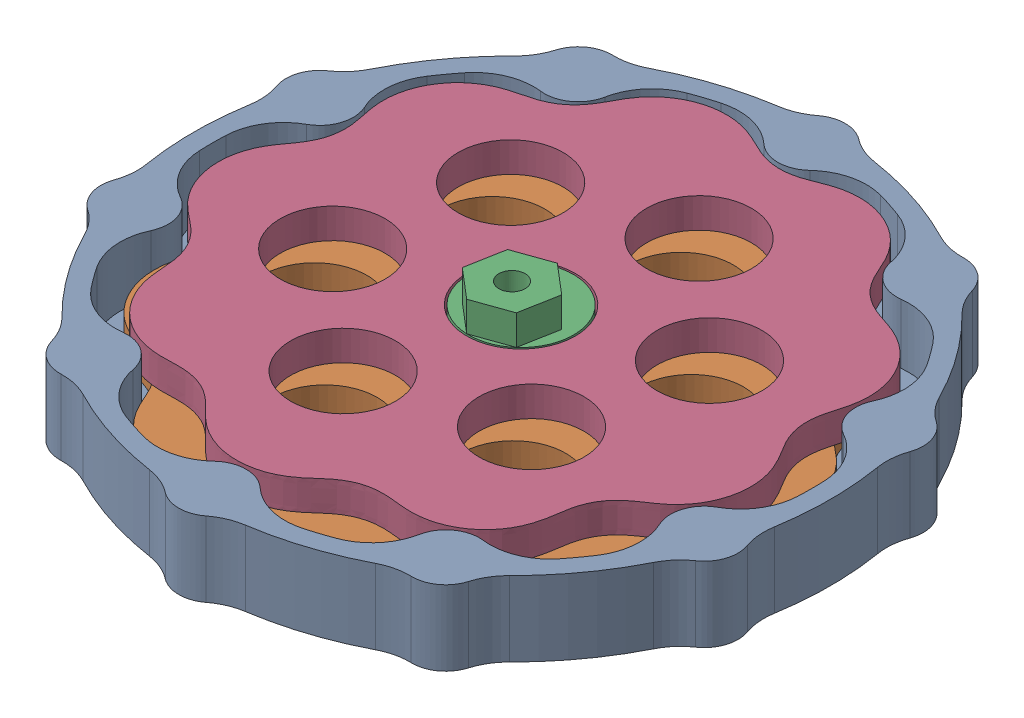
SolidWorks assembly TestPartAssem, configuration Default. Lengths in mm.
Overall size (86.43 14 90.22).
4 component instances, 3 part files, 10 mates.
Components (placement in the parent):
- cycloid_stator-1: cycloid_stator [Default] at (-40.2168 46.6857 65.8886) size (85.08 10 90)
- cycloidal_disk-1: cycloidal_disk [Default] at (-39.5465 48.6857 67.773) x (0.977505 0 0.210911) z (0 1 0) size (72.37 73.18 4)
- cycloid_shaft-1: cycloid_shaft [Default] at (-40.2168 46.6857 65.8886) x (0.335157 0 0.942162) z (-0.942162 0 0.335157) size (18 14 14)
- cycloidal_disk-2: cycloidal_disk [Default] at (-40.8871 56.6857 64.0043) x (-0.977505 0 -0.210911) z (0 -1 0) size (72.37 73.18 4)
Mates (geometry in assembly coordinates):
- Coincident6: coincident: plane of cycloid_stator-1 through (-40.2168 46.6857 65.8886) normal (0 -1 0); plane of cycloid_shaft-1 through (-40.2168 46.6857 65.8886) normal (0 -1 0)
- Concentric9: concentric: cylinder of cycloid_stator-1 through (-40.2168 46.6857 65.8886) axis (0 1 0) radius 5.25; cylinder of cycloid_shaft-1 through (-40.2168 48.6857 65.8886) axis (0 -1 0) radius 5
- Coincident7: coincident: plane of cycloidal_disk-1 through (-75.7142 52.6857 59.9692) normal (0 1 0); plane of cycloid_shaft-1 through (-39.5465 52.6857 67.773) normal (0 1 0)
- Coincident8: coincident: plane of cycloidal_disk-2 through (-4.7194 52.6857 71.808) normal (0 -1 0); plane of cycloid_shaft-1 through (-39.5465 52.6857 67.773) normal (0 1 0)
- Concentric12: concentric: cylinder of cycloidal_disk-1 through (-39.5465 48.6857 67.773) axis (0 1 0) radius 7.25; cylinder of cycloid_shaft-1 through (-39.5465 52.6857 67.773) axis (0 -1 0) radius 7
- Tangent38: tangent: circle of assembly; circle of cycloid_stator-1; face of cycloidal_disk-1
- Tangent39: tangent: circle of assembly; circle of cycloid_stator-1; face of cycloidal_disk-1
- Tangent43: tangent: circle of assembly; circle of cycloid_stator-1; face of cycloidal_disk-2
- Tangent44: tangent: circle of assembly; circle of cycloid_stator-1; face of cycloidal_disk-2
- Concentric15: concentric: cylinder of cycloid_shaft-1 through (-40.8871 56.6857 64.0043) axis (0 -1 0) radius 7; cylinder of cycloidal_disk-2 through (-40.8871 56.6857 64.0043) axis (0 -1 0) radius 7.25
